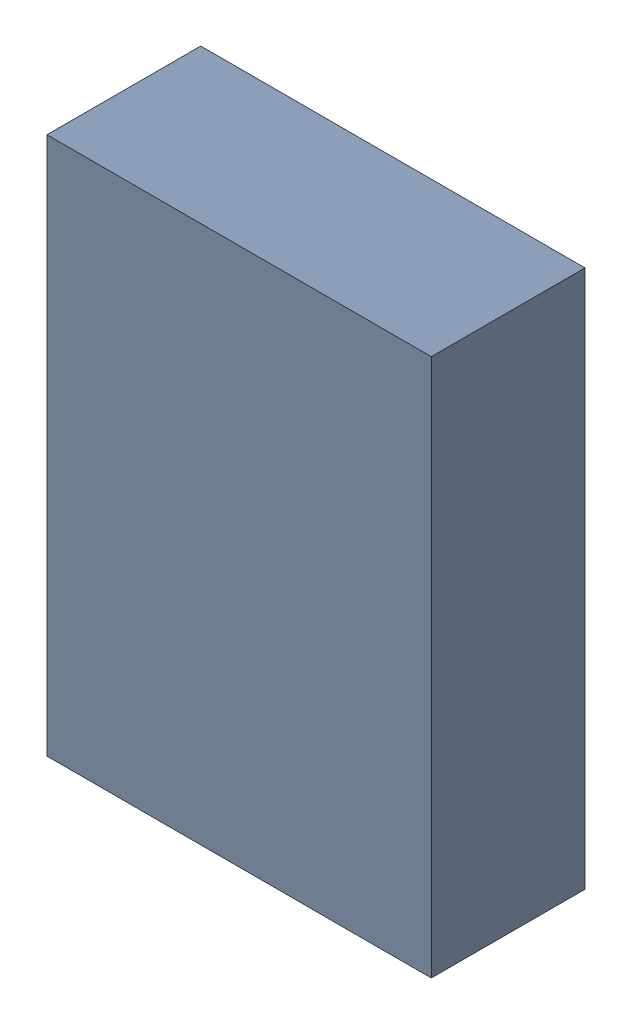
SolidWorks assembly Kanaloa_v2.0.0_Loko_10, configuration Default. Lengths in mm.
Overall size (2.5 3.5 1).
2 component instances, 1 part files, 0 mates.
Components (placement in the parent):
- 378153280_1-1: 378153280_1 [Default] at (76.1024 74.8538 0) size (2.5 3.5 1)
  - Extruded_33-1: Extruded_33 [Default] at origin size (2.5 3.5 1)
